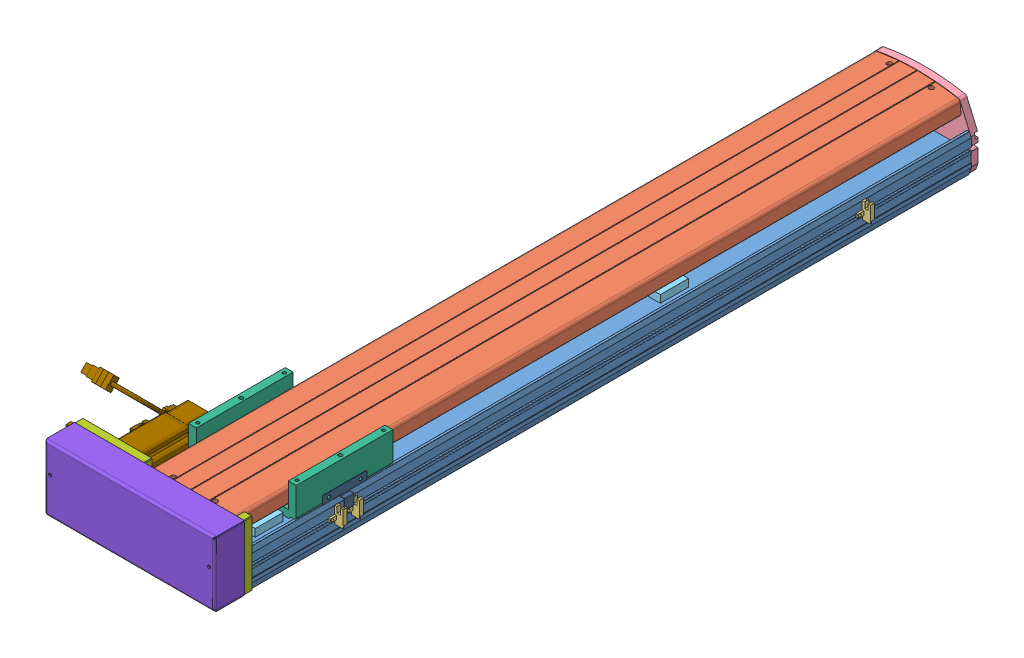
SolidWorks assembly S17M-BR-400W, configuration 默认. Lengths in mm.
Overall size (345.86 114.69 1201.01).
13 component instances, 10 part files, 40 mates.
Components (placement in the parent):
- T17-R-011底座^S17M-BR-400W-1: T17-R-011底座^S17M-BR-400W [默认] at origin size (170 60 1131) (virtual)
- T17S-L-007上盖^S17M-BR-400W-2: T17S-L-007上盖^S17M-BR-400W [Default] at (0 82 571.5) size (137.82 27.5 1143) (virtual)
- 672 传感器^S17M-BR-400W-1: 672 传感器^S17M-BR-400W [默认] at (91.7485 42.15 975.1) x (1 0 0) z (0 0 -1) size (13.5 27.4 26.1) (virtual)
- 672 传感器^S17M-BR-400W-2: 672 传感器^S17M-BR-400W [默认] at (91.7485 42.15 1001.2) x (1 0 0) z (0 0 -1) size (13.5 27.4 26.1) (virtual)
- 672 传感器^S17M-BR-400W-3: 672 传感器^S17M-BR-400W [默认] at (91.7485 42.15 171.65) x (1 0 0) z (0 0 -1) size (13.5 27.4 26.1) (virtual)
- T17S-L-001侧面板^S17M-BR-400W-1: T17S-L-001侧面板^S17M-BR-400W [默认] at (0 1 -11) size (169 101.5 11) (virtual)
- 滑座S17M^S17M-BR-400W-1: 滑座S17M^S17M-BR-400W [默认] at (0 75.7 432) x (-1 0 0) z (0 1 0) size (144.4 44 43.7) (virtual)
- 滑台S17M^S17M-BR-400W-1: 滑台S17M^S17M-BR-400W [默认] at (0 75.7 909) x (-1 0 0) z (0 1 0) size (169.2 152 78.7) (virtual)
- 滑座S17M^S17M-BR-400W-3: 滑座S17M^S17M-BR-400W [默认] at (0 75.7 1069) x (-1 0 0) z (0 1 0) size (144.4 44 43.7) (virtual)
- 电机板S17M-BR-60^S17M-BR-400W-1: 电机板S17M-BR-60^S17M-BR-400W [默认] at (-48.3502 52.2 1143) x (-1 0 0) z (0 0 -1) size (267 102 12) (virtual)
- 罩壳S17M-BLR^S17M-BR-400W-1: 罩壳S17M-BLR^S17M-BR-400W [Default] at (-48.3502 52.2 1188) x (1 0 0) z (0 0 -1) size (267.28 102.01 47.01) (virtual)
- 400W电机ECMA-C20604RS^S17M-BR-400W-1: 400W电机ECMA-C20604RS^S17M-BR-400W [Default] at (-129.9985 49.95 1083.65) x (0 -1 0) z (-1 0 0) size (94.25 160.75 147.38) (virtual)
-  外置感应片ST14-17^S17M-BR-400W-2:  外置感应片ST14-17^S17M-BR-400W [默认] at (85.2 62.2 985) x (0 0 -1) z (1 0 0) size (70 30 7.6) (virtual)
Mates (geometry in assembly coordinates):
- 重合148: coincident: plane of T17-R-011底座^S17M-BR-400W-1 through (0 0 0) normal (0 0 -1); plane of T17S-L-007上盖^S17M-BR-400W-2 through (66.7465 75.75 0) normal (0 0 -1)
- 重合153: coincident: plane of T17-R-011底座^S17M-BR-400W-1 through (0 0 0) normal (1 0 0); plane of T17S-L-007上盖^S17M-BR-400W-2 through (0 82 571.5) normal (1 0 0)
- 重合157: coincident: plane of 672 传感器^S17M-BR-400W-1 through (84.9985 53.25 968.8) normal (-1 0 0); plane of 672 传感器^S17M-BR-400W-3 through (84.9985 53.25 165.35) normal (-1 0 0)
- 重合159: coincident: plane of 672 传感器^S17M-BR-400W-1 through (84.9985 53.25 968.8) normal (0 1 0); plane of 672 传感器^S17M-BR-400W-3 through (84.9985 53.25 165.35) normal (0 1 0)
- 重合160: coincident: plane of 672 传感器^S17M-BR-400W-1 through (84.9985 53.25 968.8) normal (0 1 0); plane of 672 传感器^S17M-BR-400W-2 through (84.9985 53.25 994.9) normal (0 1 0)
- 距离20: distance = 31.55 mm: plane of T17-R-011底座^S17M-BR-400W-1 through (0 -0.5 1131) normal (0 -1 0); plane of 672 传感器^S17M-BR-400W-2 through (84.9985 31.05 994.9) normal (0 -1 0)
- 距离21: distance = 165.35 mm: plane of 672 传感器^S17M-BR-400W-3 through (98.4985 31.05 165.35) normal (0 0 -1); plane of T17-R-011底座^S17M-BR-400W-1 through (0 0 0) normal (0 0 -1)
- 重合168: coincident: plane of T17-R-011底座^S17M-BR-400W-1 through (84.9985 0 1131) normal (1 0 0); plane of 672 传感器^S17M-BR-400W-2 through (84.9985 53.25 994.9) normal (-1 0 0)
- 重合174: coincident: plane of T17-R-011底座^S17M-BR-400W-1 through (0 0 0) normal (0 0 -1); plane of T17S-L-001侧面板^S17M-BR-400W-1 through (0.0037 -247.5005 0) normal (0 0 1)
- 重合183: coincident: plane of T17-R-011底座^S17M-BR-400W-1 through (0 0 0) normal (1 0 0); plane of T17S-L-001侧面板^S17M-BR-400W-1 through (0 1 -11) normal (1 0 0)
- 距离23: distance = 82.5 mm: plane of T17S-L-007上盖^S17M-BR-400W-2 through (0 82 571.5) normal (0 1 0); plane of T17-R-011底座^S17M-BR-400W-1 through (0 -0.5 1131) normal (0 -1 0)
- 距离26: distance = 1 mm: plane of T17-R-011底座^S17M-BR-400W-1 through (0 0 0) normal (0 1 0); plane of T17S-L-001侧面板^S17M-BR-400W-1 through (0 1 -11) normal (0 1 0)
- 重合211: coordinate: point of T17-R-011底座^S17M-BR-400W-1; point of assembly
- 距离27: distance = 110 mm: plane of 滑台S17M^S17M-BR-400W-1 through (-113.7999 109.5 909) normal (0 1 0); plane of T17-R-011底座^S17M-BR-400W-1 through (0 -0.5 1131) normal (0 -1 0)
- 宽度1: width: plane of 滑台S17M^S17M-BR-400W-1 through (-84.6 65.3 1061) normal (-1 0 0); plane of 滑台S17M^S17M-BR-400W-1 through (84.6 111.2 1061) normal (1 0 0); plane of T17-R-011底座^S17M-BR-400W-1 through (84.4985 0 1131) normal (1 0 0); plane of T17-R-011底座^S17M-BR-400W-1 through (-84.4985 0 1131) normal (-1 0 0)
- 宽度2: width: plane of 滑台S17M^S17M-BR-400W-1 through (-84.6 65.3 1061) normal (-1 0 0); plane of 滑台S17M^S17M-BR-400W-1 through (84.6 111.2 1061) normal (1 0 0); plane of 滑座S17M^S17M-BR-400W-1 through (72.2 32 476) normal (1 0 0); plane of 滑座S17M^S17M-BR-400W-1 through (-72.2 32 476) normal (-1 0 0)
- 距离29: distance = 5 mm: plane of 滑座S17M^S17M-BR-400W-1 through (40 70.7 476) normal (0 1 0); plane of 滑台S17M^S17M-BR-400W-1 through (-40 75.7 1061) normal (0 1 0)
- 重合221: coincident: plane of 滑座S17M^S17M-BR-400W-1 through (-40 75.7 476) normal (0 1 0); plane of 滑座S17M^S17M-BR-400W-3 through (-40 75.7 1113) normal (0 1 0)
- 重合222: coincident: plane of 滑座S17M^S17M-BR-400W-1 through (-72.2 32 476) normal (-1 0 0); plane of 滑座S17M^S17M-BR-400W-3 through (-72.2 32 1113) normal (-1 0 0)
- 距离30: distance = 8 mm: plane of 滑座S17M^S17M-BR-400W-3 through (81.6 65.3 1069) normal (0 0 -1); plane of 滑台S17M^S17M-BR-400W-1 through (81.6 65.3 1061) normal (0 0 1)
- 距离31: distance: plane of 滑座S17M^S17M-BR-400W-3 through (81.6 65.3 1069) normal (0 0 -1); plane of 滑座S17M^S17M-BR-400W-1 through (81.6 65.3 476) normal (0 0 1)
- 距离32: distance = 1.7 mm: plane of 电机板S17M-BR-60^S17M-BR-400W-1 through (85.1498 1.2 1131) normal (0 -1 0); plane of T17-R-011底座^S17M-BR-400W-1 through (0 -0.5 1131) normal (0 -1 0)
- 重合224: coincident: plane of T17-R-011底座^S17M-BR-400W-1 through (0 0 1131) normal (0 0 1); plane of 电机板S17M-BR-60^S17M-BR-400W-1 through (-48.3502 52.2 1131) normal (0 0 -1)
- 重合225: coincident: plane of T17-R-011底座^S17M-BR-400W-1 through (84.9985 0 1131) normal (1 0 0); plane of 电机板S17M-BR-60^S17M-BR-400W-1 through (85.1498 1.2 1131) normal (1 0 0)
- 重合226: coincident: plane of 电机板S17M-BR-60^S17M-BR-400W-1 through (-48.3502 52.2 1143) normal (0 0 1); plane of 罩壳S17M-BLR^S17M-BR-400W-1 through (81.6498 103.2 1143) normal (0 0 -1)
- 重合227: coincident: plane of 电机板S17M-BR-60^S17M-BR-400W-1 through (85.1498 103.2 1131) normal (0 1 0); plane of 罩壳S17M-BLR^S17M-BR-400W-1 through (-48.3502 103.2 1188) normal (0 1 0)
- 重合228: coincident: plane of 电机板S17M-BR-60^S17M-BR-400W-1 through (-181.8502 1.2 1131) normal (-1 0 0); plane of 罩壳S17M-BLR^S17M-BR-400W-1 through (-181.8502 52.2 1188) normal (-1 0 0)
- 相切1: tangent: plane of 电机板S17M-BR-60^S17M-BR-400W-1 through (-124.3502 24.95 1143) normal (0 1 0); cylinder of 400W电机ECMA-C20604RS^S17M-BR-400W-1 through (-129.9985 49.95 1131) axis (0 0 1) radius 25
- 重合229: coincident: plane of 电机板S17M-BR-60^S17M-BR-400W-1 through (-48.3502 52.2 1131) normal (0 0 -1); plane of 400W电机ECMA-C20604RS^S17M-BR-400W-1 through (-161.0442 80.9957 1131) normal (0 0 1)
- 平行2: parallel: plane of 电机板S17M-BR-60^S17M-BR-400W-1 through (85.1498 103.2 1131) normal (0 1 0); line of 400W电机ECMA-C20604RS^S17M-BR-400W-1 through (-104.9985 79.8016 1131) axis (-1 0 0)
- 距离33: distance = 22 mm: line of 400W电机ECMA-C20604RS^S17M-BR-400W-1 through (-159.8502 24.95 1131) axis (0 1 0); plane of 电机板S17M-BR-60^S17M-BR-400W-1 through (-181.8502 1.2 1131) normal (-1 0 0)
- 重合233: coincident: plane of T17-R-011底座^S17M-BR-400W-1 through (84.9985 0 1131) normal (1 0 0); plane of 672 传感器^S17M-BR-400W-1 through (84.9985 53.25 968.8) normal (-1 0 0)
- 重合234: coincident: plane of 672 传感器^S17M-BR-400W-1 through (87.9985 34.25 985) normal (0 0 1); plane of 672 传感器^S17M-BR-400W-2 through (87.9985 34.25 985) normal (0 0 -1)
- 重合235: coincident: plane of 滑台S17M^S17M-BR-400W-1 through (84.6 111.2 1061) normal (1 0 0); plane of  外置感应片ST14-17^S17M-BR-400W-2 through (84.6 62.2 985) normal (-1 0 0)
- 同心1: concentric: cylinder of 滑台S17M^S17M-BR-400W-1 through (84.6 68.2 960) axis (1 0 0) radius 2.1; cylinder of  外置感应片ST14-17^S17M-BR-400W-2 through (85.2 68.2 960) axis (1 0 0) radius 2.75
- 同心2: concentric: cylinder of 滑台S17M^S17M-BR-400W-1 through (84.6 68.2 1010) axis (1 0 0) radius 2.1; circle of  外置感应片ST14-17^S17M-BR-400W-2
- LimitDistance1: limit distance = 7.5 mm: line of 672 传感器^S17M-BR-400W-1 through (87.9985 35.25 985) axis (0 1 0); plane of  外置感应片ST14-17^S17M-BR-400W-2 through (91.1 60.6 977.5) normal (0 0 -1)
- 距离35: distance = 214 mm: line of 672 传感器^S17M-BR-400W-1 through (87.9985 35.25 985) axis (0 1 0); plane of 罩壳S17M-BLR^S17M-BR-400W-1 through (-48.3502 52.2 1190) normal (0 0 1)
- 距离36: distance = 45 mm: cylinder of 400W电机ECMA-C20604RS^S17M-BR-400W-1 through (-129.9985 49.95 1160) axis (0 0 -1) radius 7; plane of T17-R-011底座^S17M-BR-400W-1 through (-84.9985 0 1131) normal (-1 0 0)
- 距离37: distance = 205 mm: cylinder of 滑台S17M^S17M-BR-400W-1 through (78 111.2 985) axis (0 1 0) radius 3; plane of 罩壳S17M-BLR^S17M-BR-400W-1 through (-48.3502 52.2 1190) normal (0 0 1)
